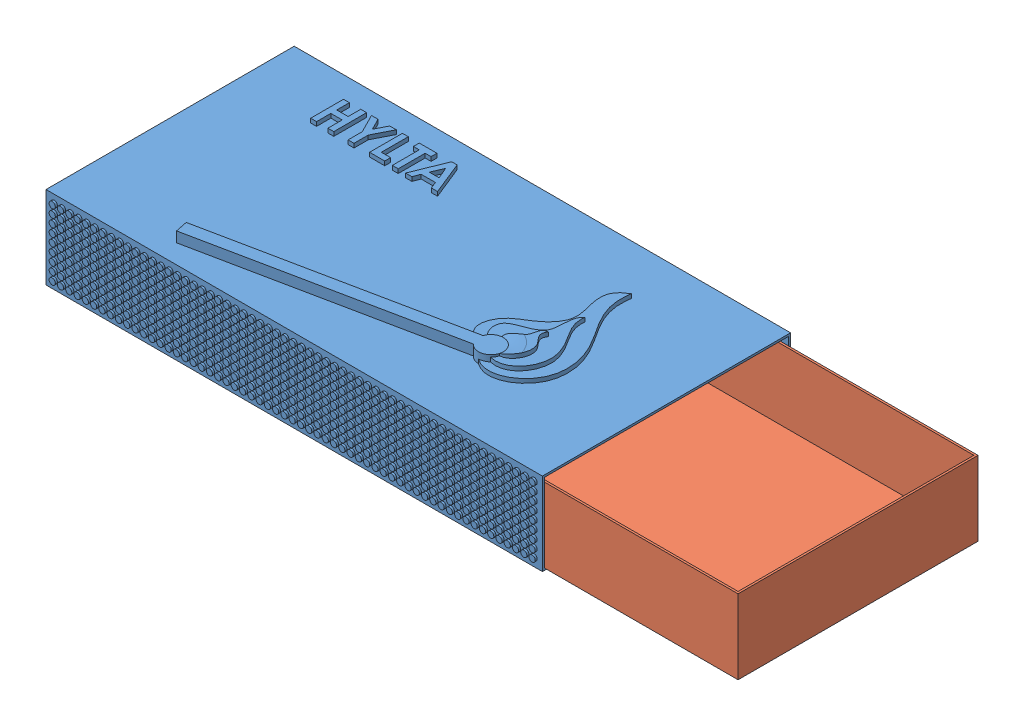
SolidWorks assembly Assem1, configuration Default. Lengths in mm.
Overall size (16.68 2.33 6.1).
2 component instances, 2 part files, 2 mates.
Components (placement in the parent):
- Lucifer doosje buitenkant-1: Lucifer doosje buitenkant [Default] at (3.621 6.5006 9.502) size (12 2.33 6.1)
- Lucifer bakje binnenkant-1: Lucifer bakje binnenkant [Default] at (8.3011 6.4506 9.552) size (12 1.8 5.8)
Mates (geometry in assembly coordinates):
- Coincident1: coincident anti-aligned: plane of Lucifer doosje buitenkant-1 through (-2.379 5.5506 12.452) normal (0 1 0); plane of Lucifer bakje binnenkant-1 through (8.3011 5.5506 9.552) normal (0 -1 0)
- Coincident2: coincident anti-aligned: plane of Lucifer doosje buitenkant-1 through (-2.379 7.4506 12.452) normal (0 0 -1); plane of Lucifer bakje binnenkant-1 through (2.3011 7.3506 12.452) normal (0 0 1)
